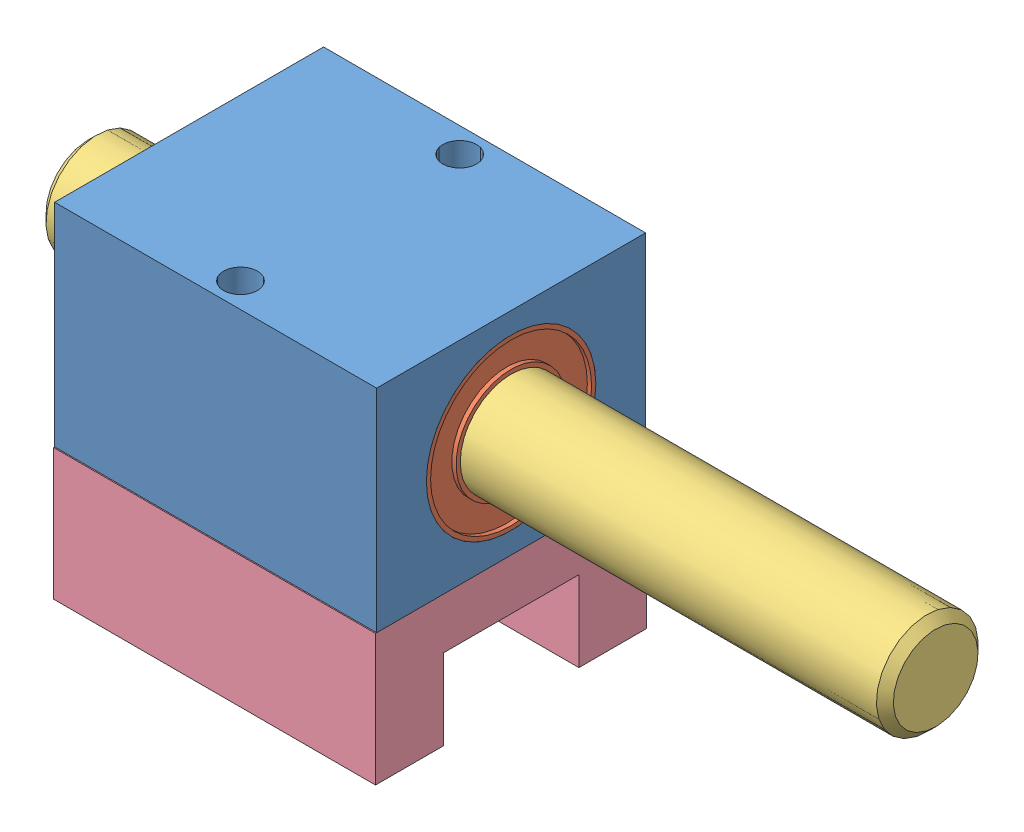
SolidWorks assembly chumaceira, configuration Default. Lengths in mm.
Overall size (50 20.25 16).
4 component instances, 4 part files, 6 mates.
Components (placement in the parent):
- chumaceira-1: chumaceira [Default] at origin size (19 12.5 15.87)
- rolamento-1: rolamento [Default] at (-9.5 6.25 0) size (19 10 10)
- eixo-1: eixo [Default] at (-15.4469 6.25 0) x (1 0 0) z (0 -0.306824 0.951766) size (50 6 6)
- espacadores-1: espacadores [Default] at (0 -7.75 0) size (19 7.75 16)
Mates (geometry in assembly coordinates):
- Concentric1: concentric anti-aligned: cylinder of chumaceira-1; cylinder of rolamento-1
- Coincident1: coincident aligned: plane of chumaceira-1 through (9.5 12.5 7.935) normal (1 0 0); plane of rolamento-1 through (9.5 6.25 0) normal (1 0 0)
- Concentric2: concentric aligned: cylinder of rolamento-1; cylinder of eixo-1
- Coincident2: coincident anti-aligned: plane of chumaceira-1 through (-9.5 0 -7.935) normal (0 -1 0); plane of espacadores-1 through (-9.5 0 8) normal (0 1 0)
- Coincident3: coincident aligned: plane of chumaceira-1 through (9.5 12.5 7.935) normal (1 0 0); plane of espacadores-1 through (9.5 0 -8) normal (1 0 0)
- Width1: width: plane of espacadores-1 through (-9.5 0 8) normal (0 0 1); plane of espacadores-1 through (-9.5 0 -8) normal (0 0 -1); plane of chumaceira-1 through (-9.5 12.5 -7.935) normal (0 0 -1); plane of chumaceira-1 through (-9.5 12.5 7.935) normal (0 0 1)
